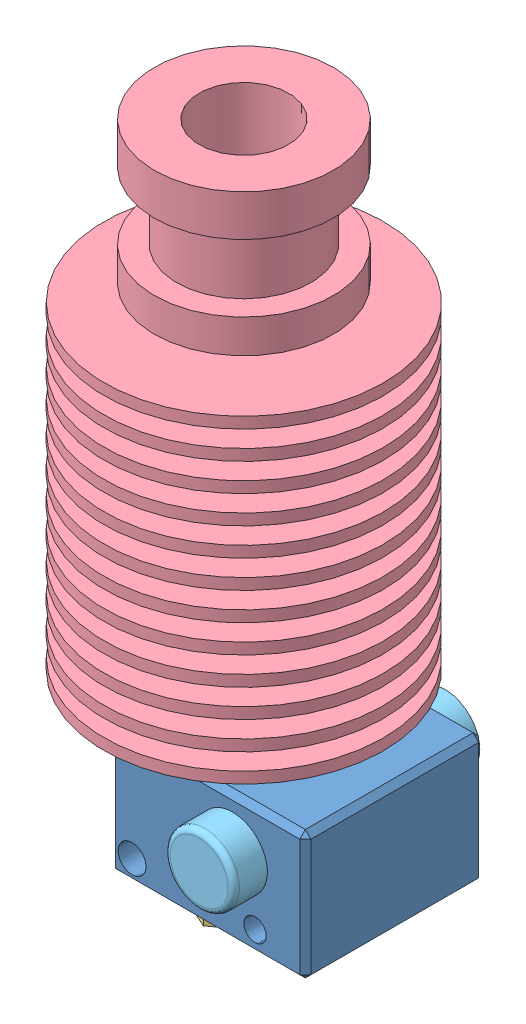
SolidWorks assembly E3D, configuration Default. Lengths in mm.
Overall size (28.79 62.3 37.75).
6 component instances, 6 part files, 10 mates.
Components (placement in the parent):
- E3D Heat Block-1: E3D Heat Block [Default] at origin size (17.5 11.5 16)
- E3D Heatbreak-1: E3D Heatbreak [Default] at (-4.75 17.5943 0) x (-0.93266 0 -0.360757) z (-0.360757 0 0.93266) size (6 22.19 6)
- E3D Nozzle-1: E3D Nozzle [Default] at (-4.75 -4 0) x (-0.097107 0 -0.995274) z (0.995274 0 -0.097107) size (8.08 12.5 7)
- E3D Heatsink-1: E3D Heatsink [1.75 Bowden] at (-4.75 34.95 0) x (0.986263 0 -0.165183) z (0.165183 0 0.986263) size (25 42.7 25)
- cartridge heater-1: cartridge heater [Default] at (2.25 7 0) x (0 0 1) z (-0.150948 -0.988542 0) size (32 6.2 6.2)
- thermistor-1: thermistor [Default] at (-6.75 2 6.5) x (-0.997586 0.069447 0) z (-0.069447 -0.997586 0) size (2 13.25 2)
Mates (geometry in assembly coordinates):
- Concentric1: concentric anti-aligned: cylinder of E3D Heat Block-1 through (-4.75 11.5 0) axis (0 1 0) radius 2.5; cylinder of E3D Heatbreak-1 through (-4.75 6.5 0) axis (0 -1 0) radius 3
- Concentric2: concentric aligned: cylinder of E3D Heatbreak-1 through (-4.75 6.5 0) axis (0 -1 0) radius 3; cylinder of E3D Heatsink-1 through (-4.75 13.6 0) axis (0 -1 0) radius 3.5
- Coincident1: coincident aligned: plane of E3D Heatbreak-1 through (-6.0557 13.6 -0.5051) normal (0 -1 0); plane of E3D Heatsink-1 through (-1.2981 13.6 -0.5781) normal (0 -1 0)
- Concentric3: concentric anti-aligned: cylinder of E3D Heat Block-1 through (-4.75 11.5 0) axis (0 1 0) radius 2.5; cylinder of E3D Nozzle-1 through (-4.75 -6 0) axis (0 -1 0) radius 3
- Coincident2: coincident anti-aligned: plane of E3D Heatbreak-1 through (-5.6827 6.5 -0.3608) normal (0 -1 0); plane of E3D Nozzle-1 through (-4.75 6.5 0) normal (0 1 0)
- Coincident3: coincident aligned: plane of E3D Heat Block-1 through (0 11.5 0) normal (0 1 0); plane of E3D Heatbreak-1 through (-7.548 11.5 -1.0823) normal (0 1 0)
- Concentric601: concentric anti-aligned: cylinder of E3D Heat Block-1 through (2.25 7 -8) axis (0 0 1) radius 3.1; cylinder of cartridge heater-1 through (2.25 7 -11) axis (0 0 -1) radius 3.1
- Width1: width aligned: plane of cartridge heater-1 through (2.6425 9.5702 11) normal (0 0 1); plane of cartridge heater-1 through (2.7179 10.0645 -11) normal (0 0 -1); plane of E3D Heat Block-1 through (-8.75 11.5 8) normal (0 0 1); plane of E3D Heat Block-1 through (-8.75 11.5 -8) normal (0 0 -1)
- Concentric602: concentric aligned: cylinder of E3D Heat Block-1 through (-6.75 2 8) axis (0 0 1) radius 1.25; circle of thermistor-1
- Tangent1: tangent anti-aligned: plane of E3D Heat Block-1 through (-6.75 2 3.5) normal (0 0 1); sphere of thermistor-1
